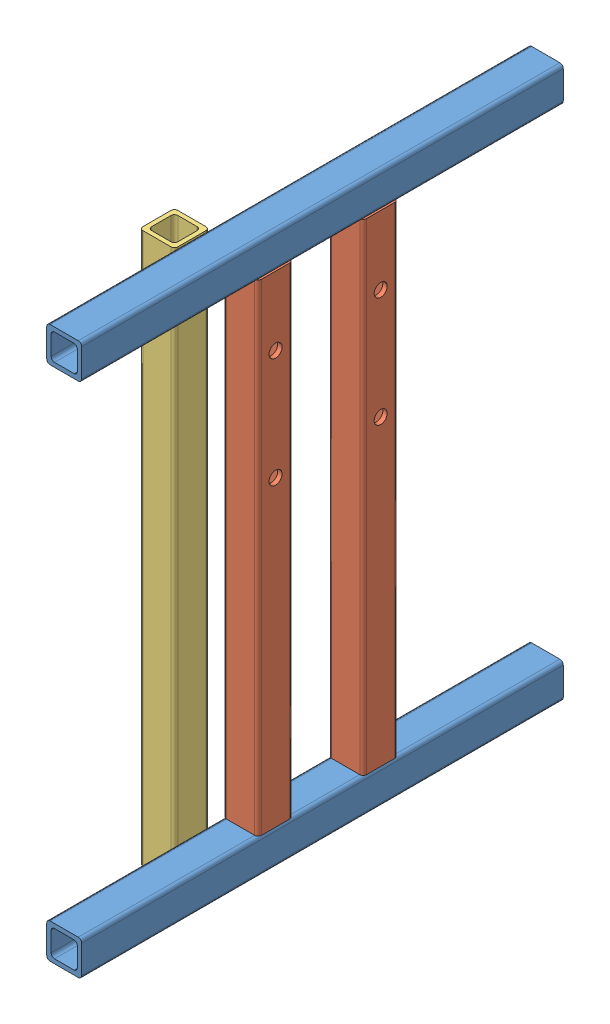
SolidWorks assembly EmpotreFlecha, configuration Predeterminado. Lengths in mm.
Overall size (50.8 400.8 350).
5 component instances, 3 part files, 12 mates.
Components (placement in the parent):
- PTR - FRENTES-1: PTR - FRENTES [Predeterminado] at (22.0255 20.1053 184.1443) size (25.4 25.4 350)
- PTR - CHUMACERAS-2: PTR - CHUMACERAS [Predeterminado] at (22.0255 7.4053 393.2443) x (-1 0 0) z (0 -1 0) size (25.4 25.4 350)
- PTR - CHUMACERAS-3: PTR - CHUMACERAS [Predeterminado] at (22.0255 7.4053 316.8443) x (-1 0 0) z (0 -1 0) size (25.4 25.4 350)
- PTR - FRENTES-2: PTR - FRENTES [Predeterminado] at (22.0255 -355.2947 184.1443) x (0 1 0) z (0 0 1) size (25.4 25.4 350)
- PTR - SOPLETE-1: PTR - SOPLETE [Predeterminado] at (-3.3745 -367.1947 428.6443) x (-1 0 0) z (0 1 0) size (25.4 25.4 400)
Mates (geometry in assembly coordinates):
- Coincidente3: coincident aligned: plane of PTR - CHUMACERAS-2 through (9.3255 -342.5947 373.0443) normal (-1 0 0); plane of PTR - CHUMACERAS-3 through (9.3255 -342.5947 327.0443) normal (-1 0 0)
- Coincidente4: coincident aligned: plane of PTR - CHUMACERAS-2 through (11.8255 -342.5947 373.0443) normal (0 -1 0); plane of PTR - CHUMACERAS-3 through (11.8255 -342.5947 327.0443) normal (0 -1 0)
- Coincidente5: coincident aligned: plane of PTR - FRENTES-1 through (9.3255 9.9053 534.1443) normal (-1 0 0); plane of PTR - CHUMACERAS-2 through (9.3255 -342.5947 373.0443) normal (-1 0 0)
- Coincidente6: coincident anti-aligned: plane of PTR - FRENTES-1 through (11.8255 7.4053 534.1443) normal (0 -1 0); plane of PTR - CHUMACERAS-2 through (11.8255 7.4053 373.0443) normal (0 1 0)
- Coincidente7: coincident aligned: plane of PTR - CHUMACERAS-3 through (9.3255 -342.5947 327.0443) normal (-1 0 0); plane of PTR - FRENTES-2 through (9.3255 -365.4947 534.1443) normal (-1 0 0)
- Coincidente8: coincident anti-aligned: plane of PTR - CHUMACERAS-3 through (11.8255 -342.5947 327.0443) normal (0 -1 0); plane of PTR - FRENTES-2 through (32.2255 -342.5947 534.1443) normal (0 1 0)
- Coincidente9: coincident aligned: plane of PTR - FRENTES-1 through (32.2255 9.9053 184.1443) normal (0 0 -1); plane of PTR - FRENTES-2 through (32.2255 -345.0947 184.1443) normal (0 0 -1)
- Coincidente10: coincident aligned: plane of PTR - FRENTES-1 through (11.8255 32.8053 534.1443) normal (0 1 0); plane of PTR - SOPLETE-1 through (-13.5745 32.8053 388.0443) normal (0 1 0)
- Coincidente11: coincident anti-aligned: plane of PTR - FRENTES-1 through (9.3255 9.9053 534.1443) normal (-1 0 0); plane of PTR - SOPLETE-1 through (9.3255 32.8053 388.0443) normal (1 0 0)
- Distancia1: distance = 10 mm anti-aligned: plane of PTR - CHUMACERAS-2 through (32.2255 -342.5947 405.9443) normal (0 0 1); plane of PTR - SOPLETE-1 through (6.8255 32.8053 415.9443) normal (0 0 -1)
- Distancia2: distance = 120 mm aligned: plane of PTR - CHUMACERAS-3 through (32.2255 -342.5947 304.1443) normal (0 0 -1); plane of PTR - FRENTES-1 through (32.2255 9.9053 184.1443) normal (0 0 -1)
- Distancia3: distance = 76.4 mm aligned: plane of PTR - CHUMACERAS-2 through (32.2255 -342.5947 380.5443) normal (0 0 -1); plane of PTR - CHUMACERAS-3 through (32.2255 -342.5947 304.1443) normal (0 0 -1)
